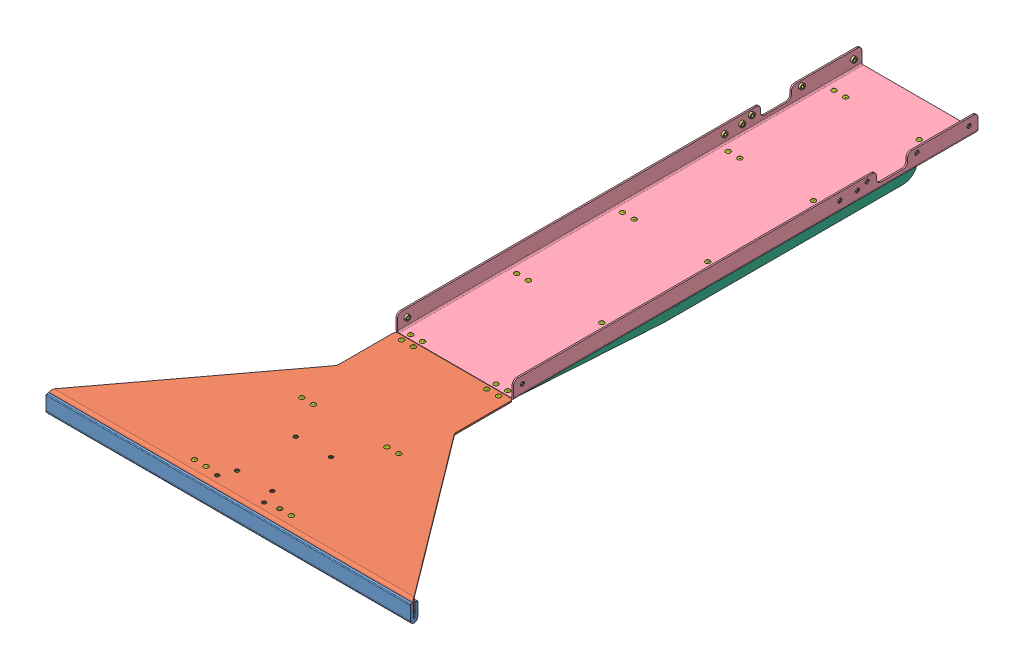
SolidWorks assembly GE-22406, configuration Default. Lengths in mm.
Overall size (788.28 338.94 1493.04).
59 component instances, 7 part files, 6 mates.
Components (placement in the parent):
- GE-22401-1: GE-22401 [Default] at (0 -31.75 1485.1063) size (787.4 38.1 15.88)
- GE-22405-1: GE-22405 [Default] at origin size (788.28 338.94 1486.69)
  - GE-22394-2: GE-22394 [Default] at (0 -3.175 1131.0938) size (788.28 306.86 482.6)
    - GE-22394-01-1: GE-22394-01 [Default] at origin size (788.28 33.34 482.6)
    - pem_clinchnut_.25_20_.054-2: pem_clinchnut_.25_20_.054 [Default] at (-50.8 4.5466 334.9625) x (0 -1 0) z (-0.471516 0 0.881858) size (5.69 11.18 11.18)
    - pem_clinchnut_.25_20_.054-3: pem_clinchnut_.25_20_.054 [Default] at (-38.1 4.5466 304.8) x (0 -1 0) z (-0.471516 0 0.881858) size (5.69 11.18 11.18)
    - pem_clinchnut_.25_20_.054-4: pem_clinchnut_.25_20_.054 [Default] at (-38.1 4.5466 177.8) x (0 -1 0) z (-0.471516 0 0.881858) size (5.69 11.18 11.18)
    - pem_clinchnut_.25_20_.054-5: pem_clinchnut_.25_20_.054 [Default] at (38.1 4.5466 177.8) x (0 -1 0) z (-0.471516 0 0.881858) size (5.69 11.18 11.18)
    - pem_clinchnut_.25_20_.054-6: pem_clinchnut_.25_20_.054 [Default] at (38.1 4.5466 304.8) x (0 -1 0) z (-0.471516 0 0.881858) size (5.69 11.18 11.18)
    - pem_clinchnut_.25_20_.054-8: pem_clinchnut_.25_20_.054 [Default] at (50.8 4.5466 334.9625) x (0 -1 0) z (0.216892 0 0.976196) size (5.69 11.18 11.18)
  - GE-22395-2: GE-22395 [Default] at (0 3.175 0) size (254 38.1 1003.3)
    - GE-22395-01-1: GE-22395-01 [Default] at origin size (254 38.1 1003.3)
    - pem_clinchnut_.25_20_.054-2: pem_clinchnut_.25_20_.054 [Default] at (-125.1966 19.05 19.05) x (1 0 0) z (0 -0.006281 0.99998) size (5.69 11.18 11.18)
    - pem_clinchnut_.25_20_.054-3: pem_clinchnut_.25_20_.054 [Default] at (125.1966 19.05 19.05) x (-1 0 0) z (0 -0.796833 -0.6042) size (5.69 11.18 11.18)
    - pem_clinchnut_.25_20_.054-4: pem_clinchnut_.25_20_.054 [Default] at (125.1966 25.4 131.7625) x (-1 0 0) z (0 -0.796833 -0.6042) size (5.69 11.18 11.18)
    - pem_clinchnut_.25_20_.054-5: pem_clinchnut_.25_20_.054 [Default] at (125.1966 25.4 239.7125) x (-1 0 0) z (0 -0.796833 -0.6042) size (5.69 11.18 11.18)
    - pem_clinchnut_.25_20_.054-6: pem_clinchnut_.25_20_.054 [Default] at (125.1966 19.05 984.25) x (-1 0 0) z (0 -0.796833 -0.6042) size (5.69 11.18 11.18)
    - pem_clinchnut_.25_20_.054-7: pem_clinchnut_.25_20_.054 [Default] at (125.1966 19.05 298.45) x (-1 0 0) z (0 -0.796833 -0.6042) size (5.69 11.18 11.18)
    - pem_clinchnut_.25_20_.054-8: pem_clinchnut_.25_20_.054 [Default] at (125.1966 19.05 260.35) x (-1 0 0) z (0 -0.796833 -0.6042) size (5.69 11.18 11.18)
    - pem_clinchnut_.25_20_.054-9: pem_clinchnut_.25_20_.054 [Default] at (-125.1966 25.4 131.7625) x (1 0 0) z (0 -0.006281 0.99998) size (5.69 11.18 11.18)
    - pem_clinchnut_.25_20_.054-10: pem_clinchnut_.25_20_.054 [Default] at (-125.1966 25.4 239.7125) x (1 0 0) z (0 -0.006281 0.99998) size (5.69 11.18 11.18)
    - pem_clinchnut_.25_20_.054-11: pem_clinchnut_.25_20_.054 [Default] at (-125.1966 19.05 984.25) x (1 0 0) z (0 -0.006281 0.99998) size (5.69 11.18 11.18)
    - pem_clinchnut_.25_20_.054-12: pem_clinchnut_.25_20_.054 [Default] at (-125.1966 19.05 298.45) x (1 0 0) z (0 -0.006281 0.99998) size (5.69 11.18 11.18)
    - pem_clinchnut_.25_20_.054-13: pem_clinchnut_.25_20_.054 [Default] at (-125.1966 19.05 260.35) x (1 0 0) z (0 -0.006281 0.99998) size (5.69 11.18 11.18)
  - GE-22397-1: GE-22397 [Default] at (-63.5 0 69.85) x (0 0 1) z (-1 0 0) size (1400.97 76.2 53.98)
  - GE-22396-2: GE-22396 [MirrorDefault] at (63.5 0 69.85) x (0 0 1) z (-1 0 0) size (1400.97 76.2 53.98)
  - rivet_.1875_.126-.25-52: rivet_.1875_.126-.25 [Default] at (-104.775 3.175 993.775) x (0.957018 0 -0.29003) z (0 1 0) size (10.01 10.01 13.03)
  - rivet_.1875_.126-.25-1: rivet_.1875_.126-.25 [Default] at (-79.375 3.175 1461.2938) x (-0.837169 0 -0.546944) z (0 1 0) size (10.01 10.01 13.03)
  - rivet_.1875_.126-.25-24: rivet_.1875_.126-.25 [Default] at (79.375 3.175 1461.2938) x (-0.837169 0 0.546944) z (0 1 0) size (10.01 10.01 13.03)
  - rivet_.1875_.126-.25-53: rivet_.1875_.126-.25 [Default] at (-104.775 3.175 1229.5187) x (-0.837169 0 -0.546944) z (0 1 0) size (10.01 10.01 13.03)
  - rivet_.1875_.126-.25-54: rivet_.1875_.126-.25 [Default] at (-79.375 3.175 1229.5187) x (-0.837169 0 -0.546944) z (0 1 0) size (10.01 10.01 13.03)
  - rivet_.1875_.126-.25-55: rivet_.1875_.126-.25 [Default] at (79.375 3.175 1229.5187) x (-0.837169 0 -0.546944) z (0 1 0) size (10.01 10.01 13.03)
  - rivet_.1875_.126-.25-56: rivet_.1875_.126-.25 [Default] at (104.775 3.175 1229.5187) x (-0.837169 0 -0.546944) z (0 1 0) size (10.01 10.01 13.03)
  - rivet_.1875_.126-.25-57: rivet_.1875_.126-.25 [Default] at (-104.775 3.175 1461.2938) x (-0.837169 0 -0.546944) z (0 1 0) size (10.01 10.01 13.03)
  - rivet_.1875_.126-.25-58: rivet_.1875_.126-.25 [Default] at (-104.775 3.175 1013.6187) x (-0.837169 0 -0.546944) z (0 1 0) size (10.01 10.01 13.03)
  - rivet_.1875_.126-.25-59: rivet_.1875_.126-.25 [Default] at (104.775 3.175 1013.6187) x (-0.837169 0 -0.546944) z (0 1 0) size (10.01 10.01 13.03)
  - rivet_.1875_.126-.25-60: rivet_.1875_.126-.25 [Default] at (79.375 3.175 1013.6187) x (-0.837169 0 -0.546944) z (0 1 0) size (10.01 10.01 13.03)
  - rivet_.1875_.126-.25-61: rivet_.1875_.126-.25 [Default] at (104.775 3.175 1461.2938) x (-0.837169 0 -0.546944) z (0 1 0) size (10.01 10.01 13.03)
  - rivet_.1875_.126-.25-62: rivet_.1875_.126-.25 [Default] at (79.375 3.175 1461.2938) x (-0.837169 0 -0.546944) z (0 1 0) size (10.01 10.01 13.03)
  - rivet_.1875_.126-.25-63: rivet_.1875_.126-.25 [Default] at (-79.375 3.175 1013.6187) x (-0.837169 0 -0.546944) z (0 1 0) size (10.01 10.01 13.03)
  - rivet_.1875_.126-.25-64: rivet_.1875_.126-.25 [Default] at (104.775 3.175 79.375) x (0.957018 0 -0.29003) z (0 1 0) size (10.01 10.01 13.03)
  - rivet_.1875_.126-.25-65: rivet_.1875_.126-.25 [Default] at (-79.375 3.175 993.775) x (0.957018 0 -0.29003) z (0 1 0) size (10.01 10.01 13.03)
  - rivet_.1875_.126-.25-66: rivet_.1875_.126-.25 [Default] at (79.375 3.175 993.775) x (0.957018 0 -0.29003) z (0 1 0) size (10.01 10.01 13.03)
  - rivet_.1875_.126-.25-67: rivet_.1875_.126-.25 [Default] at (104.775 3.175 993.775) x (0.957018 0 -0.29003) z (0 1 0) size (10.01 10.01 13.03)
  - rivet_.1875_.126-.25-68: rivet_.1875_.126-.25 [Default] at (104.775 3.175 765.175) x (0.957018 0 -0.29003) z (0 1 0) size (10.01 10.01 13.03)
  - rivet_.1875_.126-.25-69: rivet_.1875_.126-.25 [Default] at (79.375 3.175 765.175) x (0.957018 0 -0.29003) z (0 1 0) size (10.01 10.01 13.03)
  - rivet_.1875_.126-.25-70: rivet_.1875_.126-.25 [Default] at (-104.775 3.175 765.175) x (0.957018 0 -0.29003) z (0 1 0) size (10.01 10.01 13.03)
  - rivet_.1875_.126-.25-71: rivet_.1875_.126-.25 [Default] at (-104.775 3.175 536.575) x (0.957018 0 -0.29003) z (0 1 0) size (10.01 10.01 13.03)
  - rivet_.1875_.126-.25-72: rivet_.1875_.126-.25 [Default] at (-79.375 3.175 536.575) x (0.957018 0 -0.29003) z (0 1 0) size (10.01 10.01 13.03)
  - rivet_.1875_.126-.25-73: rivet_.1875_.126-.25 [Default] at (-79.375 3.175 765.175) x (0.957018 0 -0.29003) z (0 1 0) size (10.01 10.01 13.03)
  - rivet_.1875_.126-.25-74: rivet_.1875_.126-.25 [Default] at (79.375 3.175 536.575) x (0.957018 0 -0.29003) z (0 1 0) size (10.01 10.01 13.03)
  - rivet_.1875_.126-.25-75: rivet_.1875_.126-.25 [Default] at (104.775 3.175 536.575) x (0.957018 0 -0.29003) z (0 1 0) size (10.01 10.01 13.03)
  - rivet_.1875_.126-.25-76: rivet_.1875_.126-.25 [Default] at (104.775 3.175 307.975) x (0.957018 0 -0.29003) z (0 1 0) size (10.01 10.01 13.03)
  - rivet_.1875_.126-.25-77: rivet_.1875_.126-.25 [Default] at (79.375 3.175 307.975) x (0.957018 0 -0.29003) z (0 1 0) size (10.01 10.01 13.03)
  - rivet_.1875_.126-.25-78: rivet_.1875_.126-.25 [Default] at (-79.375 3.175 307.975) x (0.957018 0 -0.29003) z (0 1 0) size (10.01 10.01 13.03)
  - rivet_.1875_.126-.25-79: rivet_.1875_.126-.25 [Default] at (-104.775 3.175 307.975) x (0.957018 0 -0.29003) z (0 1 0) size (10.01 10.01 13.03)
  - rivet_.1875_.126-.25-80: rivet_.1875_.126-.25 [Default] at (-104.775 3.175 79.375) x (0.957018 0 -0.29003) z (0 1 0) size (10.01 10.01 13.03)
  - rivet_.1875_.126-.25-81: rivet_.1875_.126-.25 [Default] at (-79.375 3.175 79.375) x (0.957018 0 -0.29003) z (0 1 0) size (10.01 10.01 13.03)
  - rivet_.1875_.126-.25-82: rivet_.1875_.126-.25 [Default] at (79.375 3.175 79.375) x (0.957018 0 -0.29003) z (0 1 0) size (10.01 10.01 13.03)
Mates (geometry in assembly coordinates):
- Coincident5863: coincident anti-aligned: plane of GE-22394-2/GE-22394-01-1 through (0 -3.175 1486.6937) normal (0 0 1); plane of GE-22401-1 through (393.7 -3.175 1486.6937) normal (0 0 -1)
- Coincident5864: coincident aligned: plane of GE-22394-2/GE-22394-01-1 through (-393.7 0 1486.6937) normal (-1 0 0); plane of GE-22401-1 through (-393.7 -33.3375 1485.1063) normal (-1 0 0)
- Coincident5865: coincident anti-aligned: plane of GE-22394-2/GE-22394-01-1 through (-393.7 -30.1625 1486.6937) normal (0 -1 0); plane of GE-22401-1 through (393.7 -31.75 1486.6937) normal (0 1 0)
- Coincident5867: coincident anti-aligned: plane of GE-22401-1 through (393.7 -3.175 1486.6937) normal (0 0 -1); plane of GE-22405-1/GE-22394-2/GE-22394-01-1 through (0 -3.175 1486.6937) normal (0 0 1)
- Coincident5868: coincident: plane of GE-22401-1 through (393.7 -3.175 1477.1687) normal (0 1 0); line of GE-22405-1/GE-22394-2/GE-22394-01-1 through (393.7 -3.175 1483.5187) axis (-1 0 0)
- Coincident5869: coincident aligned: plane of GE-22401-1 through (0 -31.75 1485.1063) normal (1 0 0); plane of GE-22405-1 through (0 0 0) normal (1 0 0)
